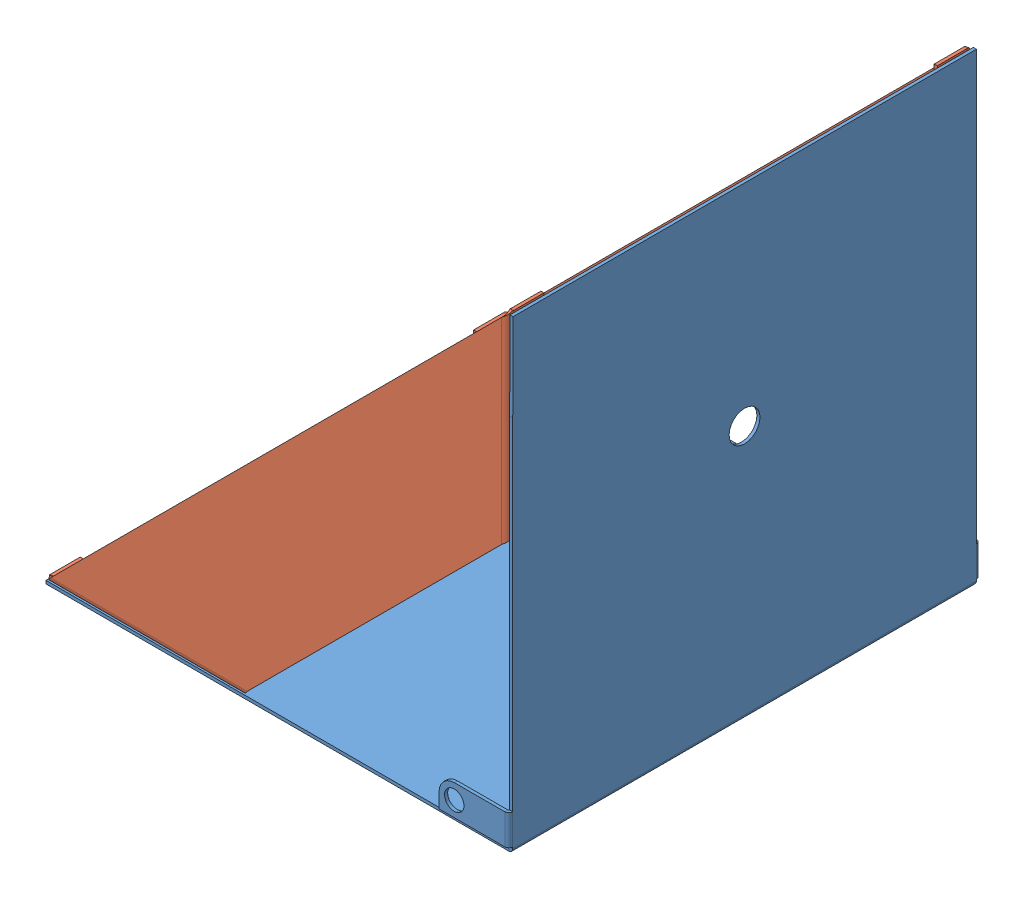
SolidWorks assembly Assem3, configuration Default. Lengths in mm.
Overall size (383.55 383.55 387.55).
4 component instances, 2 part files, 0 mates.
Components (placement in the parent):
- MainBodyAssem-1: MainBodyAssem [Default] at (-134.6015 -9.9419 38.5268) size (383.55 383.55 387.55)
  - MainBody-1: MainBody [Default] at (-11.3224 52.2437 481.7014) size (383.54 381.86 387.55)
  - DiagonalHolder-1: DiagonalHolder [Default] at (369.6776 433.2437 480.5768) x (0 -1 0) z (1 0 0) size (381.01 29.58 381.01)
  - DiagonalHolder-2: DiagonalHolder [Default] at (-11.3224 52.2437 103.2414) x (1 0 0) z (0 -1 0) size (381.01 29.58 381.01)
